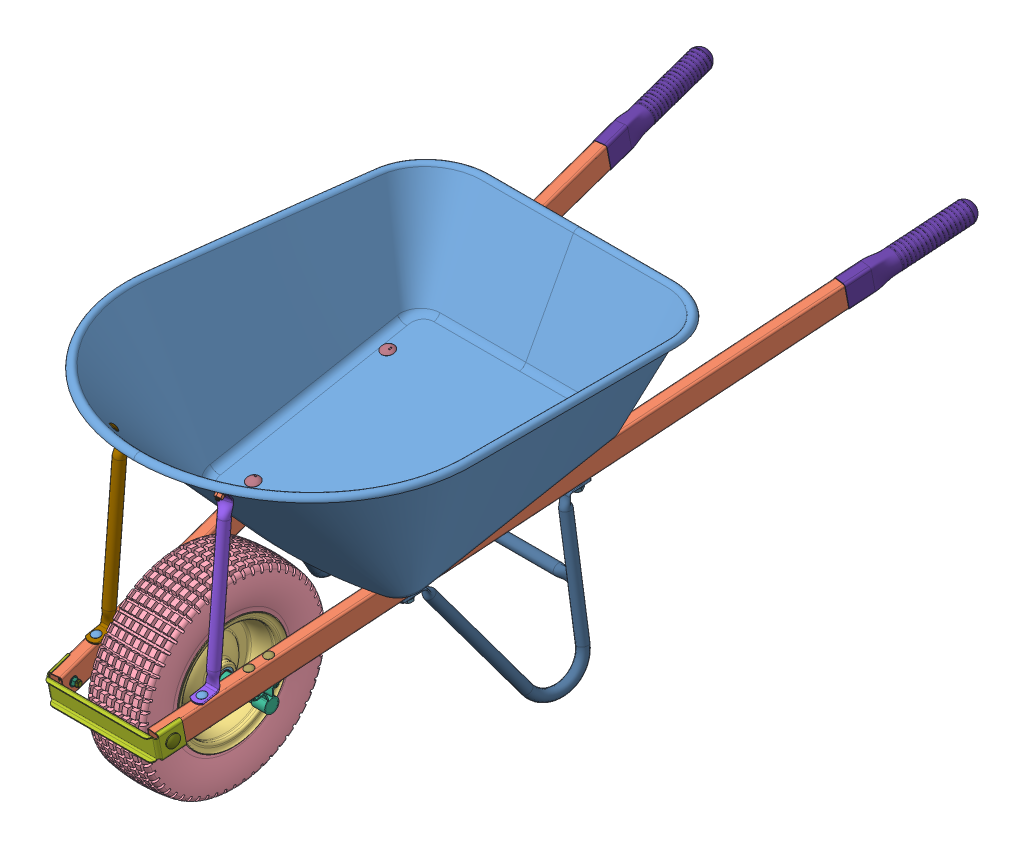
SolidWorks assembly True Temper Whellbarrow Assy, configuration Default. Lengths in mm.
Overall size (696.37 676.21 1573.81).
46 component instances, 20 part files, 93 mates.
Components (placement in the parent):
- Wheelbarrow fill tray-1: Wheelbarrow fill tray [Default] at origin size (696.37 363.5 942.02)
- Wheelbarrow Lifting Arm-1: Wheelbarrow Lifting Arm [Default] at (102.1952 208.3067 -25.6255) x (0.993643 -0.021099 0.110583) z (-0.112578 -0.18623 0.976035) size (38.83 50.1 1565)
- Wheelbarrow Lifting Arm-2: Wheelbarrow Lifting Arm [opp hand] at (-102.1942 208.3067 -25.6256) x (0.993643 0.021099 -0.110583) z (0.112578 -0.18623 0.976035) size (38.83 50.1 1565)
- Whellbarrow Wheel-1: Whellbarrow Wheel [Default] at (0.0012 190 -236.4752) size (124 398.25 398.25)
  - Wheelbarrow Wheel half rim-1: Wheelbarrow Wheel half rim [Default] at origin size (56.6 233.53 233.53)
  - Wheelbarrow Wheel half rim-2: Wheelbarrow Wheel half rim [Default] x (-1 0 0) z (0 -0.076485 -0.997071) size (56.6 233.53 233.53)
  - wheel barrow tire-1: wheel barrow tire [Default] at origin size (124 398.25 398.25)
  - 2349K424_Permanently Lubricated Ball Bearing-1: 2349K424_Permanently Lubricated Ball Bearing [2349K424] at (-30 0 0) x (0 0 1) z (-1 0 0) size (52 52 15)
  - 2349K424_Permanently Lubricated Ball Bearing-2: 2349K424_Permanently Lubricated Ball Bearing [2349K424] at (30 0 0) x (0 0 1) z (-1 0 0) size (52 52 15)
- Wheelbarrow Wheel Axle-1: Wheelbarrow Wheel Axle [Default] at (0.0012 190 -236.4752) x (1 0 0) z (0 -0.187421 0.98228) size (275 47.5 52)
- Wheelbarrow Front Brace2-1: Wheelbarrow Front Brace2 [Default] at (0.0158 207.0391 -19.9155) x (1 0.000003 -0.000018) z (0.000019 -0.187421 0.98228) size (243.5 54.35 62.59)
- Wheelbarrow Front Brace Bucket  Left-1: Wheelbarrow Front Brace Bucket  Left [Default] at (110 233.014 -21.7278) size (34.83 374.53 76.91)
- Wheelbarrow Front Bucket Brace Right-2: Wheelbarrow Front Bucket Brace Right [Default] at (-110 233.014 -21.7278) x (-1 0 0) z (0 0 -1) size (34.83 374.53 76.91)
- Wheelbarrow Leg setting Brackets-1: Wheelbarrow Leg setting Brackets [Default] at (0 0.4661 -2.5771) size (493.82 338.41 363.4)
- 90030A111_Heavy Duty External Retaining Ring-1: 90030A111_Heavy Duty External Retaining Ring [90030A111] at (38.5012 189.0586 -236.4752) x (0 0 1) z (-1 0 0) size (28.12 33 2)
- 90030A111_Heavy Duty External Retaining Ring-2: 90030A111_Heavy Duty External Retaining Ring [90030A111] at (-38.4988 190 -236.4752) x (0 0 -1) z (1 0 0) size (28.12 33 2)
- 98930A136_Steel Square-Neck Carriage Bolts-8: 98930A136_Steel Square-Neck Carriage Bolts [98930A136] at (123.6183 272.185 -201.4132) x (0.993643 -0.021099 0.110583) z (0 0.98228 0.187421) size (18 18 65.31)
- 98930A136_Steel Square-Neck Carriage Bolts-5: 98930A136_Steel Square-Neck Carriage Bolts [98930A136] at (127.8998 279.2676 -238.5335) x (0.993643 -0.021099 0.110583) z (0 0.98228 0.187421) size (18 18 65.31)
- 98930A136_Steel Square-Neck Carriage Bolts-7: 98930A136_Steel Square-Neck Carriage Bolts [98930A136] at (-126.9052 279.2887 -238.6442) x (0.993643 0.021099 -0.110583) z (0 0.98228 0.187421) size (18 18 65.31)
- 98930A136_Steel Square-Neck Carriage Bolts-6: 98930A136_Steel Square-Neck Carriage Bolts [98930A136] at (-122.6237 272.2061 -201.5238) x (0.993643 0.021099 -0.110583) z (0 0.98228 0.187421) size (18 18 65.31)
- 98930A208_Steel Square-Neck Carriage Bolts-1: 98930A208_Steel Square-Neck Carriage Bolts [98930A208] at (-193.2223 353.5056 -816.4962) x (-0.112578 0.18623 -0.976035) z (0 -0.98228 -0.187421) size (26.6 26.6 77.64)
- 98930A208_Steel Square-Neck Carriage Bolts-2: 98930A208_Steel Square-Neck Carriage Bolts [98930A208] at (-156.4068 292.6232 -497.4098) x (-0.993643 -0.021099 0.110583) z (0 -0.98228 -0.187421) size (26.6 26.6 77.64)
- 98930A208_Steel Square-Neck Carriage Bolts-3: 98930A208_Steel Square-Neck Carriage Bolts [98930A208] at (156.4068 292.6232 -497.4098) x (0.993643 -0.021099 0.110583) z (0 -0.98228 -0.187421) size (26.6 26.6 77.64)
- 98930A208_Steel Square-Neck Carriage Bolts-4: 98930A208_Steel Square-Neck Carriage Bolts [98930A208] at (193.2223 353.5056 -816.4962) x (0.112578 0.18623 -0.976035) z (0 -0.98228 -0.187421) size (26.6 26.6 77.64)
- 96595A104_High-Strength Steel Serrated Flange Locknut-1: 96595A104_High-Strength Steel Serrated Flange Locknut [96595A104] at (156.4068 258.8575 -503.8524) x (-0.951424 0.057704 -0.302427) z (0 -0.98228 -0.187421) size (26 26 12.95)
- 96595A104_High-Strength Steel Serrated Flange Locknut-2: 96595A104_High-Strength Steel Serrated Flange Locknut [96595A104] at (193.2223 319.7151 -822.9435) x (-0.122005 -0.186021 0.974941) z (0 -0.98228 -0.187421) size (26 26 12.95)
- 96595A104_High-Strength Steel Serrated Flange Locknut-3: 96595A104_High-Strength Steel Serrated Flange Locknut [96595A104] at (-156.4068 258.8575 -503.8524) x (-0.122005 -0.186021 0.974941) z (0 -0.98228 -0.187421) size (26 26 12.95)
- 96595A104_High-Strength Steel Serrated Flange Locknut-4: 96595A104_High-Strength Steel Serrated Flange Locknut [96595A104] at (-193.2223 319.7151 -822.9435) x (-0.122005 -0.186021 0.974941) z (0 -0.98228 -0.187421) size (26 26 12.95)
- 96595A102_High-Strength Steel Serrated Flange Locknut-1: 96595A102_High-Strength Steel Serrated Flange Locknut [96595A102] at (127.8998 215.1248 -250.7721) x (0.214259 0.183069 -0.959468) z (0 -0.98228 -0.187421) size (17.9 17.9 8.52)
- 96595A102_High-Strength Steel Serrated Flange Locknut-2: 96595A102_High-Strength Steel Serrated Flange Locknut [96595A102] at (123.6183 208.0421 -213.6518) x (0.924142 -0.071604 0.37528) z (0 -0.98228 -0.187421) size (17.9 17.9 8.52)
- 96595A102_High-Strength Steel Serrated Flange Locknut-3: 96595A102_High-Strength Steel Serrated Flange Locknut [96595A102] at (-122.6237 208.0632 -213.7624) x (0.924142 -0.071604 0.37528) z (0 -0.98228 -0.187421) size (17.9 17.9 8.52)
- 96595A102_High-Strength Steel Serrated Flange Locknut-4: 96595A102_High-Strength Steel Serrated Flange Locknut [96595A102] at (-126.9052 215.1459 -250.8828) x (0.924142 -0.071604 0.37528) z (0 -0.98228 -0.187421) size (17.9 17.9 8.52)
- 98930A332_Steel Square-Neck Carriage Bolts-1: 98930A332_Steel Square-Neck Carriage Bolts [98930A332] at (121.4138 212.0513 -46.1845) x (0.112578 0.18623 -0.976035) z (0.993643 -0.021099 0.110583) size (26.6 26.6 47.55)
- 96595A102_High-Strength Steel Serrated Flange Locknut-5: 96595A102_High-Strength Steel Serrated Flange Locknut [96595A102] at (84.4066 212.8371 -50.3031) x (-0.031025 -0.995565 0.088815) z (-0.993643 0.021099 -0.110583) size (17.9 17.9 8.52)
- 98930A332_Steel Square-Neck Carriage Bolts-2: 98930A332_Steel Square-Neck Carriage Bolts [98930A332] at (-121.3837 212.0504 -46.1801) x (0.112578 -0.18623 0.976035) z (-0.993643 -0.021099 0.110583) size (26.6 26.6 47.55)
- 96595A102_High-Strength Steel Serrated Flange Locknut-6: 96595A102_High-Strength Steel Serrated Flange Locknut [96595A102] at (-84.4047 212.8357 -50.2955) x (0.08986 -0.74036 0.666178) z (0.993643 0.021099 -0.110583) size (17.9 17.9 8.52)
- grip-1: grip [opp hand] at (251.9569 455.6377 -1318.6934) x (-0.993643 0.021099 -0.110583) z (0.112578 0.18623 -0.976035) size (42.91 55.05 256.59)
- grip-2: grip [opp hand] at (-251.3597 455.061 -1318.8722) x (0.993643 0.021099 -0.110583) z (-0.112578 0.18623 -0.976035) size (42.91 55.05 256.59)
- 98930A114_Steel Square-Neck Carriage Bolts-1: 98930A114_Steel Square-Neck Carriage Bolts [98930A114] at (113.4585 610.9021 -155.4808) x (0.965926 -0.021199 -0.257949) z (-0.183878 0.645173 -0.74158) size (18 18 21.26)
- 98930A114_Steel Square-Neck Carriage Bolts-2: 98930A114_Steel Square-Neck Carriage Bolts [98930A114] at (-113.2923 611.4852 -156.1511) x (0.965926 0.021199 0.257949) z (0.183878 0.645173 -0.74158) size (18 18 21.26)
- 98930A136_Steel Square-Neck Carriage Bolts(1)-1: 98930A136_Steel Square-Neck Carriage Bolts(1) [98930A136] at (110 259.1266 -116.4334) x (-0.112578 -0.18623 0.976035) z (0 0.98228 0.187421) size (18 18 65.31)
- 98930A136_Steel Square-Neck Carriage Bolts(1)-2: 98930A136_Steel Square-Neck Carriage Bolts(1) [98930A136] at (-111.954 259.0799 -116.1886) x (0.112578 -0.18623 0.976035) z (0 0.98228 0.187421) size (18 18 65.31)
- 96595A102_High-Strength Steel Serrated Flange Locknut(1)-1: 96595A102_High-Strength Steel Serrated Flange Locknut(1) [96595A102] at (110 194.3943 -128.7844) x (-0.877786 0.089785 -0.470564) z (0 -0.98228 -0.187421) size (17.9 17.9 8.52)
- 96595A102_High-Strength Steel Serrated Flange Locknut(1)-2: 96595A102_High-Strength Steel Serrated Flange Locknut(1) [96595A102] at (-111.954 194.3476 -128.5396) x (-0.550982 0.156406 -0.819729) z (0 -0.98228 -0.187421) size (17.9 17.9 8.52)
- 96595A102_High-Strength Steel Serrated Flange Locknut(1)-3: 96595A102_High-Strength Steel Serrated Flange Locknut(1) [96595A102] at (115.9538 602.1467 -145.4172) x (0.980586 0.068118 -0.183878) z (0.183878 -0.645173 0.74158) size (17.9 17.9 8.52)
- 96595A102_High-Strength Steel Serrated Flange Locknut(1)-4: 96595A102_High-Strength Steel Serrated Flange Locknut(1) [96595A102] at (-115.9538 602.1467 -145.4172) x (0.980586 -0.068118 0.183878) z (-0.183878 -0.645173 0.74158) size (17.9 17.9 8.52)
Mates (geometry in assembly coordinates):
- Coincident1: coincident anti-aligned: plane of Wheelbarrow fill tray-1 through (0 475.7667 -1294.0015) normal (0 -0.98228 -0.187421); plane of Wheelbarrow Lifting Arm-1 through (248.5436 489.1088 -1363.9283) normal (0 0.98228 0.187421)
- Coincident2: coincident: plane of Wheelbarrow Lifting Arm-1 through (269.4101 443.4809 -1370.2275) normal (0.993643 -0.021099 0.110583)
- Concentric1: concentric anti-aligned: circle of Wheelbarrow tray-1; cylinder of Whellbarrow Wheel-1/Wheelbarrow Wheel half rim-1 through (0.0012 190 -236.4752) axis (-1 0 0) radius 26.5
- Parallel1: parallel anti-aligned: plane of Wheelbarrow Lifting Arm-1 through (248.5436 439.9949 -1373.2994) normal (0 -0.98228 -0.187421); plane of Wheelbarrow Wheel Axle-1 through (137.5012 219.6098 -218.2547) normal (0 0.98228 0.187421)
- Concentric2: concentric aligned: cylinder of Whellbarrow Wheel-1/Wheelbarrow Wheel half rim-1 through (0.0012 190 -236.4752) axis (-1 0 0) radius 26.5; cylinder of Wheelbarrow Wheel Axle-1 through (137.5012 190 -236.4752) axis (-1 0 0) radius 12.5
- Width2: width aligned: plane of Whellbarrow Wheel-1/Wheelbarrow Wheel half rim-1 through (1.5012 257.3202 -236.4752) normal (1 0 0); plane of Wheelbarrow Wheel Axle-1 through (-1.4988 257.123 -241.6241) normal (-1 0 0); plane of Whellbarrow Wheel-1/Wheelbarrow Wheel half rim-2 through (137.5012 190 -236.4752) normal (1 0 0); plane of Wheelbarrow Wheel Axle-1 through (-137.4988 190 -236.4752) normal (-1 0 0)
- Coincident9: coincident anti-aligned: plane of Wheelbarrow Lifting Arm-1 through (248.5436 489.1088 -1363.9283) normal (0 0.98228 0.187421); plane of Wheelbarrow Front Brace Bucket  Left-1 through (97.5 254.6464 -135.1039) normal (0 -0.98228 -0.187421)
- Distance2: distance = 110 mm: plane of assembly through (0 0 0) normal (1 0 0); plane of assembly; plane of Wheelbarrow Front Brace Bucket  Left-1 through (110 233.014 -21.7278) normal (1 0 0)
- Coincident11: coincident: point of assembly; face of Wheelbarrow fill tray-1; point of Wheelbarrow Front Brace Bucket  Left-1
- Coincident12: coincident anti-aligned: plane of Wheelbarrow Lifting Arm-1 through (248.5436 439.9949 -1373.2994) normal (0 -0.98228 -0.187421); plane of Wheelbarrow Leg setting Brackets-1 through (203.6487 330.8878 -801.4661) normal (0 0.98228 0.187421)
- Coincident13: coincident aligned: plane of Wheelbarrow Leg setting Brackets-1 through (0 0.4661 -2.5771) normal (1 0 0)
- Distance3: distance = 500 mm: moEndPointRef_w of Wheelbarrow Leg setting Brackets-1; line of Wheelbarrow Lifting Arm-1 through (93.7492 183.9291 -31.251) axis (0.993643 -0.021099 0.110583)
- Concentric3: concentric anti-aligned: cylinder of Wheelbarrow Wheel Axle-1 through (39.5012 190 -236.4752) axis (-1 0 0) radius 11.95; cylinder of 90030A111_Heavy Duty External Retaining Ring-1 through (37.5012 190 -236.4752) axis (1 0 0) radius 14.0586
- Coincident14: coincident anti-aligned: plane of Wheelbarrow Wheel Axle-1 through (37.5012 190 -236.4752) normal (1 0 0); circle of 90030A111_Heavy Duty External Retaining Ring-1
- Concentric5: concentric anti-aligned: cylinder of Wheelbarrow Wheel Axle-1 through (-39.4988 190 -236.4752) axis (1 0 0) radius 11.95; cylinder of 90030A111_Heavy Duty External Retaining Ring-2 through (-37.4988 190 -236.4752) axis (-1 0 0) radius 11.6
- Coincident15: coincident anti-aligned: plane of Wheelbarrow Wheel Axle-1 through (-37.4988 190 -236.4752) normal (-1 0 0); circle of 90030A111_Heavy Duty External Retaining Ring-2
- Coincident16: coincident anti-aligned: plane of Wheelbarrow Lifting Arm-1 through (119.8385 219.1954 -216.355) normal (-0.112578 -0.18623 0.976035); plane of 98930A136_Steel Square-Neck Carriage Bolts-8 through (128.3639 208.5366 -217.4054) normal (0.112578 0.18623 -0.976035)
- Coincident17: coincident anti-aligned: plane of Wheelbarrow Lifting Arm-1 through (248.5436 489.1088 -1363.9283) normal (0 0.98228 0.187421); plane of 98930A136_Steel Square-Neck Carriage Bolts-8 through (124.5774 269.0567 -210.6286) normal (0 -0.98228 -0.187421)
- Coincident18: coincident anti-aligned: plane of Wheelbarrow Lifting Arm-1 through (124.12 226.2781 -253.4754) normal (-0.112578 -0.18623 0.976035); plane of 98930A136_Steel Square-Neck Carriage Bolts-5 through (132.6455 215.6192 -254.5258) normal (0.112578 0.18623 -0.976035)
- Coincident19: coincident anti-aligned: plane of Wheelbarrow Lifting Arm-1 through (248.5436 489.1088 -1363.9283) normal (0 0.98228 0.187421); plane of 98930A136_Steel Square-Neck Carriage Bolts-5 through (128.859 276.1394 -247.749) normal (0 -0.98228 -0.187421)
- Coincident20: coincident anti-aligned: plane of Wheelbarrow Lifting Arm-2 through (-130.685 224.5203 -244.2628) normal (0.993643 0.021099 -0.110583); plane of 98930A136_Steel Square-Neck Carriage Bolts-7 through (-131.6509 215.6403 -254.6364) normal (-0.993643 -0.021099 0.110583)
- Coincident21: coincident anti-aligned: plane of Wheelbarrow Lifting Arm-2 through (-130.685 224.5203 -244.2628) normal (-0.112578 0.18623 -0.976035); plane of 98930A136_Steel Square-Neck Carriage Bolts-7 through (-122.1595 214.2235 -247.2108) normal (0.112578 -0.18623 0.976035)
- Coincident22: coincident anti-aligned: plane of Wheelbarrow Lifting Arm-2 through (-265.4346 488.7502 -1362.0485) normal (0 0.98228 0.187421); plane of 98930A136_Steel Square-Neck Carriage Bolts-7 through (-127.8643 276.1605 -247.8596) normal (0 -0.98228 -0.187421)
- Coincident23: coincident anti-aligned: plane of Wheelbarrow Lifting Arm-2 through (-126.4034 217.4376 -207.1425) normal (0.993643 0.021099 -0.110583); plane of 98930A136_Steel Square-Neck Carriage Bolts-6 through (-127.3693 208.5577 -217.516) normal (-0.993643 -0.021099 0.110583)
- Coincident24: coincident anti-aligned: plane of Wheelbarrow Lifting Arm-2 through (-126.4034 217.4376 -207.1425) normal (-0.112578 0.18623 -0.976035); plane of 98930A136_Steel Square-Neck Carriage Bolts-6 through (-117.878 207.1409 -210.0905) normal (0.112578 -0.18623 0.976035)
- Coincident25: coincident anti-aligned: plane of Wheelbarrow Lifting Arm-2 through (-265.4346 488.7502 -1362.0485) normal (0 0.98228 0.187421); plane of 98930A136_Steel Square-Neck Carriage Bolts-6 through (-123.5828 269.0778 -210.7393) normal (0 -0.98228 -0.187421)
- Concentric10: concentric anti-aligned: cylinder of Wheelbarrow Leg setting Brackets-1 through (-193.2223 334.4493 -820.1321) axis (0 0.98228 0.187421) radius 7.5; cylinder of 98930A208_Steel Square-Neck Carriage Bolts-1 through (-193.2223 384.5456 -810.5737) axis (0 -0.98228 -0.187421) radius 6.1894
- Coincident27: coincident anti-aligned: plane of Wheelbarrow fill tray-1 through (0 476.7489 -1293.8141) normal (0 0.98228 0.187421); plane of 98930A208_Steel Square-Neck Carriage Bolts-1 through (-187.2605 384.6722 -811.2372) normal (0 -0.98228 -0.187421)
- Concentric11: concentric anti-aligned: cylinder of Wheelbarrow Leg setting Brackets-1 through (193.2223 334.4493 -820.1321) axis (0 0.98228 0.187421) radius 7.5; cylinder of 98930A208_Steel Square-Neck Carriage Bolts-4 through (193.2223 384.5456 -810.5737) axis (0 -0.98228 -0.187421) radius 6.1894
- Coincident30: coincident anti-aligned: plane of Wheelbarrow fill tray-1 through (0 476.7489 -1293.8141) normal (0 0.98228 0.187421); plane of 98930A208_Steel Square-Neck Carriage Bolts-4 through (199.1842 384.419 -809.9102) normal (0 -0.98228 -0.187421)
- Concentric13: concentric anti-aligned: cylinder of Wheelbarrow Leg setting Brackets-1 through (156.4068 273.5423 -501.0505) axis (0 0.98228 0.187421) radius 7.5; cylinder of 98930A208_Steel Square-Neck Carriage Bolts-3 through (156.4068 323.6632 -491.4873) axis (0 -0.98228 -0.187421) radius 6.1894
- Concentric15: concentric anti-aligned: circle of Wheelbarrow Leg setting Brackets-1; cylinder of 98930A208_Steel Square-Neck Carriage Bolts-2 through (-156.4068 323.6632 -491.4873) axis (0 -0.98228 -0.187421) radius 6.1894
- Coincident31: coincident anti-aligned: plane of Wheelbarrow fill tray-1 through (-149.3819 728.981 -408.4562) normal (-0.112578 0.18623 -0.976035); plane of 98930A208_Steel Square-Neck Carriage Bolts-2 through (-162.0016 318.4176 -485.337) normal (0.112578 -0.18623 0.976035)
- Coincident32: coincident anti-aligned: plane of Wheelbarrow fill tray-1 through (150.9756 731.3426 -420.8336) normal (-0.112578 -0.18623 0.976035); plane of 98930A208_Steel Square-Neck Carriage Bolts-3 through (163.4313 320.7827 -497.7326) normal (0.112578 0.18623 -0.976035)
- Coincident33: coincident anti-aligned: plane of Wheelbarrow fill tray-1 through (0 476.7489 -1293.8141) normal (0 0.98228 0.187421); plane of 98930A208_Steel Square-Neck Carriage Bolts-3 through (155.7314 322.5458 -485.6311) normal (0 -0.98228 -0.187421)
- Coincident34: coincident anti-aligned: plane of Wheelbarrow fill tray-1 through (0 476.7489 -1293.8141) normal (0 0.98228 0.187421); plane of 98930A208_Steel Square-Neck Carriage Bolts-2 through (-157.0823 324.7806 -497.3435) normal (0 -0.98228 -0.187421)
- Concentric16: concentric aligned: cylinder of Wheelbarrow Leg setting Brackets-1 through (156.4068 273.5423 -501.0505) axis (0 0.98228 0.187421) radius 7.5; cylinder of 96595A104_High-Strength Steel Serrated Flange Locknut-1 through (156.4068 268.8767 -501.9407) axis (0 0.98228 0.187421) radius 13
- Coincident37: coincident anti-aligned: plane of Wheelbarrow Leg setting Brackets-1 through (141.476 266.7572 -481.2281) normal (0 -0.98228 -0.187421); plane of 96595A104_High-Strength Steel Serrated Flange Locknut-1 through (159.6065 272.4979 -511.3156) normal (0 0.98228 0.187421)
- Concentric17: concentric aligned: cylinder of Wheelbarrow Leg setting Brackets-1 through (193.2223 334.4493 -820.1321) axis (0 0.98228 0.187421) radius 7.5; cylinder of 96595A104_High-Strength Steel Serrated Flange Locknut-2 through (193.2223 329.7344 -821.0318) axis (0 0.98228 0.187421) radius 13
- Coincident38: coincident anti-aligned: plane of Wheelbarrow Leg setting Brackets-1 through (203.6487 327.941 -802.0284) normal (0 -0.98228 -0.187421); plane of 96595A104_High-Strength Steel Serrated Flange Locknut-2 through (182.9077 331.7401 -821.9399) normal (0 0.98228 0.187421)
- Concentric18: concentric aligned: cylinder of Wheelbarrow Leg setting Brackets-1 through (-193.2223 334.4493 -820.1321) axis (0 0.98228 0.187421) radius 7.5; cylinder of 96595A104_High-Strength Steel Serrated Flange Locknut-4 through (-193.2223 329.7344 -821.0318) axis (0 0.98228 0.187421) radius 13
- Concentric19: concentric aligned: cylinder of Wheelbarrow Leg setting Brackets-1 through (-156.4068 273.5423 -501.0505) axis (0 0.98228 0.187421) radius 7.5; cylinder of 96595A104_High-Strength Steel Serrated Flange Locknut-3 through (-156.4068 268.8767 -501.9407) axis (0 0.98228 0.187421) radius 13
- Coincident39: coincident anti-aligned: plane of Wheelbarrow Leg setting Brackets-1 through (-203.6487 327.941 -802.0284) normal (0 -0.98228 -0.187421); plane of 96595A104_High-Strength Steel Serrated Flange Locknut-4 through (-203.537 331.7401 -821.9399) normal (0 0.98228 0.187421)
- Coincident40: coincident anti-aligned: plane of Wheelbarrow Leg setting Brackets-1 through (-141.476 266.7572 -481.2281) normal (0 -0.98228 -0.187421); plane of 96595A104_High-Strength Steel Serrated Flange Locknut-3 through (-166.7215 270.8825 -502.8488) normal (0 0.98228 0.187421)
- Concentric20: concentric anti-aligned: circle of 98930A136_Steel Square-Neck Carriage Bolts-2; cylinder of 96595A102_High-Strength Steel Serrated Flange Locknut-1 through (127.8998 221.8043 -249.4977) axis (0 0.98228 0.187421) radius 8.95
- Concentric21: concentric aligned: cylinder of Wheelbarrow Lifting Arm-1 through (127.8998 234.2792 -247.1174) axis (0 -0.98228 -0.187421) radius 4.25; cylinder of 98930A136_Steel Square-Neck Carriage Bolts-5 through (127.8998 215.6159 -250.6784) axis (0 -0.98228 -0.187421) radius 4
- Coincident41: coincident anti-aligned: plane of Wheelbarrow Wheel Axle-1 through (137.5012 224.3413 -256.3918) normal (0 -0.98228 -0.187421); plane of 96595A102_High-Strength Steel Serrated Flange Locknut-1 through (135.231 222.6816 -247.6931) normal (0 0.98228 0.187421)
- Concentric22: concentric aligned: cylinder of Wheelbarrow Lifting Arm-1 through (123.6183 227.1966 -209.9971) axis (0 -0.98228 -0.187421) radius 4.25; cylinder of 98930A136_Steel Square-Neck Carriage Bolts-8 through (123.6183 208.5333 -213.5581) axis (0 -0.98228 -0.187421) radius 4
- Concentric23: concentric anti-aligned: circle of 98930A136_Steel Square-Neck Carriage Bolts-8; cylinder of 96595A102_High-Strength Steel Serrated Flange Locknut-2 through (123.6183 214.7216 -212.3773) axis (0 0.98228 0.187421) radius 8.95
- Coincident43: coincident anti-aligned: plane of Wheelbarrow Wheel Axle-1 through (137.5012 214.5954 -205.3133) normal (0 -0.98228 -0.187421); plane of 96595A102_High-Strength Steel Serrated Flange Locknut-2 through (120.7508 214.6004 -205.3391) normal (0 0.98228 0.187421)
- Concentric24: concentric anti-aligned: circle of 98930A136_Steel Square-Neck Carriage Bolts-6; cylinder of 96595A102_High-Strength Steel Serrated Flange Locknut-3 through (-122.6237 214.7427 -212.488) axis (0 0.98228 0.187421) radius 8.95
- Concentric25: concentric anti-aligned: circle of 98930A136_Steel Square-Neck Carriage Bolts-7; cylinder of 96595A102_High-Strength Steel Serrated Flange Locknut-4 through (-126.9052 221.8254 -249.6083) axis (0 0.98228 0.187421) radius 8.95
- Coincident44: coincident anti-aligned: plane of Wheelbarrow Wheel Axle-1 through (-137.4988 224.3413 -256.3918) normal (0 -0.98228 -0.187421); plane of 96595A102_High-Strength Steel Serrated Flange Locknut-4 through (-129.7727 221.7041 -242.5701) normal (0 0.98228 0.187421)
- Coincident45: coincident anti-aligned: plane of Wheelbarrow Wheel Axle-1 through (-137.4988 214.5954 -205.3133) normal (0 -0.98228 -0.187421); plane of 96595A102_High-Strength Steel Serrated Flange Locknut-3 through (-125.4911 214.6215 -205.4498) normal (0 0.98228 0.187421)
- Coincident46: coincident anti-aligned: plane of Wheelbarrow Lifting Arm-1 through (269.4101 443.4809 -1370.2275) normal (0.993643 -0.021099 0.110583); plane of Wheelbarrow Front Brace2-1 through (114.6157 227.5167 -20.5276) normal (-0.993643 0.021099 -0.110583)
- Coincident47: coincident: plane of Wheelbarrow Lifting Arm-1 through (248.5436 489.1088 -1363.9283) normal (0 0.98228 0.187421); line of Wheelbarrow Front Brace2-1 through (109.4488 232.7097 -20.1327) axis (0.112578 0.18623 -0.976035)
- Coincident48: coincident aligned: plane of Wheelbarrow Lifting Arm-1 through (110.6411 187.4995 -28.6214) normal (-0.112578 -0.18623 0.976035); plane of Wheelbarrow Front Brace2-1 through (109.4488 234.6742 -19.7579) normal (-0.112578 -0.18623 0.976035)
- Concentric27: concentric aligned: cylinder of Wheelbarrow Lifting Arm-1 through (92.3557 212.6683 -49.4184) axis (-0.993643 0.021099 -0.110583) radius 7.5; cylinder of 98930A332_Steel Square-Neck Carriage Bolts-1 through (79.4384 212.9426 -50.856) axis (-0.993643 0.021099 -0.110583) radius 13.3
- Coincident51: coincident anti-aligned: plane of Wheelbarrow Front Brace2-1 through (-122.0367 222.2605 -65.8107) normal (0 -0.98228 -0.187421); plane of 98930A332_Steel Square-Neck Carriage Bolts-1 through (115.9244 219.6031 -51.8827) normal (0 0.98228 0.187421)
- Coincident52: coincident anti-aligned: plane of Wheelbarrow Front Brace2-1 through (116.603 227.4745 -20.3064) normal (0.993643 -0.021099 0.110583); plane of 98930A332_Steel Square-Neck Carriage Bolts-1 through (119.1841 225.1629 -43.94) normal (-0.993643 0.021099 -0.110583)
- Concentric28: concentric anti-aligned: cylinder of Wheelbarrow Lifting Arm-1 through (92.3557 212.6683 -49.4184) axis (-0.993643 0.021099 -0.110583) radius 7.5; cylinder of 96595A102_High-Strength Steel Serrated Flange Locknut-5 through (91.1634 212.6936 -49.5511) axis (0.993643 -0.021099 0.110583) radius 8.95
- Coincident53: coincident anti-aligned: plane of Wheelbarrow Lifting Arm-1 through (244.5691 444.0084 -1372.992) normal (-0.993643 0.021099 -0.110583); plane of 96595A102_High-Strength Steel Serrated Flange Locknut-5 through (91.5435 213.3564 -41.9887) normal (0.993643 -0.021099 0.110583)
- Concentric29: concentric aligned: cylinder of Wheelbarrow Lifting Arm-2 through (-92.3539 212.6669 -49.4108) axis (0.993643 0.021099 -0.110583) radius 7.5; cylinder of 98930A332_Steel Square-Neck Carriage Bolts-2 through (-79.4083 212.9418 -50.8516) axis (0.993643 0.021099 -0.110583) radius 13.3
- Coincident59: coincident anti-aligned: plane of Wheelbarrow Lifting Arm-2 through (-86.1966 220.2328 -55.1833) normal (0 -0.98228 -0.187421); plane of 98930A332_Steel Square-Neck Carriage Bolts-2 through (-114.4646 217.2371 -39.4826) normal (0 0.98228 0.187421)
- Tangent2: tangent: plane of Wheelbarrow Front Brace2-1 through (-116.5716 227.4737 -20.3021) normal (-0.993639 -0.021106 0.110619); circle of 98930A332_Steel Square-Neck Carriage Bolts-2
- Concentric30: concentric anti-aligned: cylinder of Wheelbarrow Lifting Arm-2 through (-92.3539 212.6669 -49.4108) axis (0.993643 0.021099 -0.110583) radius 7.5; cylinder of 96595A102_High-Strength Steel Serrated Flange Locknut-6 through (-91.1615 212.6922 -49.5435) axis (-0.993643 -0.021099 0.110583) radius 8.95
- Coincident63: coincident anti-aligned: plane of Wheelbarrow Lifting Arm-2 through (-244.5681 444.0084 -1372.9921) normal (0.993643 0.021099 -0.110583); plane of 96595A102_High-Strength Steel Serrated Flange Locknut-6 through (-92.8629 207.624 -54.9465) normal (-0.993643 -0.021099 0.110583)
- Coincident64: coincident anti-aligned: plane of Wheelbarrow Lifting Arm-1 through (269.4101 443.4809 -1370.2275) normal (0.993643 -0.021099 0.110583); plane of grip-1 through (269.4101 444.0703 -1370.115) normal (-0.993643 0.021099 -0.110583)
- Coincident66: coincident anti-aligned: plane of Wheelbarrow Lifting Arm-1 through (248.5436 489.1088 -1363.9283) normal (0 0.98228 0.187421); plane of grip-1 through (266.0317 488.7375 -1361.9821) normal (0 -0.98228 -0.187421)
- Concentric31: concentric aligned: cylinder of Wheelbarrow Lifting Arm-2 through (-278.3784 499.7562 -1553.1207) axis (0.112578 -0.18623 0.976035) radius 19; cylinder of grip-2 through (-278.3784 499.7562 -1553.1207) axis (0.112578 -0.18623 0.976035) radius 21
- Parallel8: parallel aligned: plane of Wheelbarrow Lifting Arm-2 through (-265.4346 488.7502 -1362.0485) normal (0 0.98228 0.187421); plane of grip-2 through (-265.4346 489.7325 -1361.8611) normal (0 0.98228 0.187421)
- Coincident71: coincident aligned: plane of Wheelbarrow Lifting Arm-2 through (-278.3784 499.7562 -1553.1207) normal (-0.112578 0.18623 -0.976035); circle of grip-2
- Coincident72: coincident aligned: plane of Wheelbarrow Lifting Arm-1 through (278.3794 499.7561 -1553.1206) normal (0.112578 0.18623 -0.976035); circle of grip-1
- Coincident74: coincident anti-aligned: plane of Wheelbarrow Front Brace Bucket  Left-1 through (111.8725 624.8972 -179.2012) normal (-0.965926 0.021199 0.257949); plane of 98930A114_Steel Square-Neck Carriage Bolts-1 through (117.6638 604.5772 -155.8448) normal (0.965926 -0.021199 -0.257949)
- Tangent3: tangent: edge_curve of Wheelbarrow fill tray-1; circle of 98930A114_Steel Square-Neck Carriage Bolts-1
- Coincident75: coincident anti-aligned: plane of Wheelbarrow Front Brace Bucket  Left-1 through (109.2915 631.5411 -172.7811) normal (-0.182143 -0.763742 -0.619291); plane of 98930A114_Steel Square-Neck Carriage Bolts-1 through (119.2266 611.1301 -150.5313) normal (0.182143 0.763742 0.619291)
- Coincident76: coincident anti-aligned: plane of Wheelbarrow Front Bucket Brace Right-2 through (-109.2915 631.5411 -172.7811) normal (0.182143 -0.763742 -0.619291); plane of 98930A114_Steel Square-Neck Carriage Bolts-2 through (-110.7728 611.8952 -148.9884) normal (-0.182143 0.763742 0.619291)
- Coincident77: coincident anti-aligned: plane of Wheelbarrow Front Bucket Brace Right-2 through (-103.5849 625.0791 -176.988) normal (-0.965926 -0.021199 -0.257949); plane of 98930A114_Steel Square-Neck Carriage Bolts-2 through (-109.21 605.3423 -154.3019) normal (0.965926 0.021199 0.257949)
- Tangent4: tangent: edge_curve of Wheelbarrow fill tray-1; circle of 98930A114_Steel Square-Neck Carriage Bolts-2
- Coincident78: coincident anti-aligned: plane of Wheelbarrow Front Brace Bucket  Left-1 through (105.2543 236.6056 -116.8824) normal (0.112578 0.18623 -0.976035); plane of 98930A136_Steel Square-Neck Carriage Bolts(1)-1 through (113.7798 193.8803 -124.0512) normal (-0.112578 -0.18623 0.976035)
- Concentric33: concentric aligned: cylinder of Wheelbarrow Lifting Arm-2 through (-111.954 202.2059 -127.0403) axis (0 -0.98228 -0.187421) radius 5; cylinder of 98930A136_Steel Square-Neck Carriage Bolts(1)-2 through (-111.954 195.4282 -128.3335) axis (0 -0.98228 -0.187421) radius 4
- Parallel9: parallel anti-aligned: plane of Wheelbarrow Front Bucket Brace Right-2 through (-116.7284 238.0225 -124.308) normal (0.993643 0.021099 -0.110583); plane of 98930A136_Steel Square-Neck Carriage Bolts(1)-2 through (-115.7337 193.8336 -123.8064) normal (-0.993643 -0.021099 0.110583)
- Coincident83: coincident anti-aligned: plane of Wheelbarrow Front Brace Bucket  Left-1 through (113.7798 236.4246 -115.9336) normal (-0.993643 0.021099 -0.110583); plane of 98930A136_Steel Square-Neck Carriage Bolts(1)-1 through (113.7798 193.8803 -124.0512) normal (0.993643 -0.021099 0.110583)
- Coincident84: coincident anti-aligned: plane of Wheelbarrow Front Brace Bucket  Left-1 through (122.5 257.6915 -134.5229) normal (0 0.98228 0.187421); plane of 98930A136_Steel Square-Neck Carriage Bolts(1)-1 through (118.4658 254.2319 -116.3908) normal (0 -0.98228 -0.187421)
- Coincident85: coincident anti-aligned: plane of Wheelbarrow Front Bucket Brace Right-2 through (-122.5 257.6915 -134.5229) normal (0 0.98228 0.187421); plane of 98930A136_Steel Square-Neck Carriage Bolts(1)-2 through (-103.4881 254.5447 -118.0304) normal (0 -0.98228 -0.187421)
- Concentric35: concentric anti-aligned: cylinder of Wheelbarrow Lifting Arm-1 through (110 202.2526 -127.285) axis (0 -0.98228 -0.187421) radius 5; cylinder of 96595A102_High-Strength Steel Serrated Flange Locknut(1)-1 through (110 201.0738 -127.5099) axis (0 0.98228 0.187421) radius 8.95
- Coincident86: coincident anti-aligned: plane of Wheelbarrow Lifting Arm-1 through (248.5436 439.9949 -1373.2994) normal (0 -0.98228 -0.187421); plane of 96595A102_High-Strength Steel Serrated Flange Locknut(1)-1 through (113.5956 203.4874 -133.7566) normal (0 0.98228 0.187421)
- Concentric36: concentric anti-aligned: cylinder of Wheelbarrow Lifting Arm-2 through (-111.954 202.2059 -127.0403) axis (0 -0.98228 -0.187421) radius 5; cylinder of 96595A102_High-Strength Steel Serrated Flange Locknut(1)-2 through (-111.954 201.0271 -127.2652) axis (0 0.98228 0.187421) radius 8.95
- Coincident87: coincident anti-aligned: plane of Wheelbarrow Lifting Arm-2 through (-265.4346 439.6362 -1371.4196) normal (0 -0.98228 -0.187421); plane of 96595A102_High-Strength Steel Serrated Flange Locknut(1)-2 through (-105.6904 202.9809 -131.1024) normal (0 0.98228 0.187421)
- Concentric37: concentric anti-aligned: circle of 98930A114_Steel Square-Neck Carriage Bolts-1; cylinder of 96595A102_High-Strength Steel Serrated Flange Locknut(1)-3 through (114.7035 606.5339 -150.4599) axis (-0.183878 0.645173 -0.74158) radius 8.95
- Coincident88: coincident anti-aligned: plane of Wheelbarrow Front Brace Bucket  Left-1 through (99.2212 594.2076 -158.9631) normal (0.183878 -0.645173 0.74158); plane of 96595A102_High-Strength Steel Serrated Flange Locknut(1)-3 through (114.9941 613.0198 -146.5075) normal (-0.183878 0.645173 -0.74158)
- Concentric38: concentric anti-aligned: circle of 98930A114_Steel Square-Neck Carriage Bolts-2; cylinder of 96595A102_High-Strength Steel Serrated Flange Locknut(1)-4 through (-114.7035 606.5339 -150.4599) axis (0.183878 0.645173 -0.74158) radius 8.95
- Coincident89: coincident anti-aligned: plane of Wheelbarrow Front Bucket Brace Right-2 through (-99.2212 594.2076 -158.9631) normal (-0.183878 -0.645173 0.74158); plane of 96595A102_High-Strength Steel Serrated Flange Locknut(1)-4 through (-114.9941 613.0198 -146.5075) normal (0.183878 0.645173 -0.74158)
